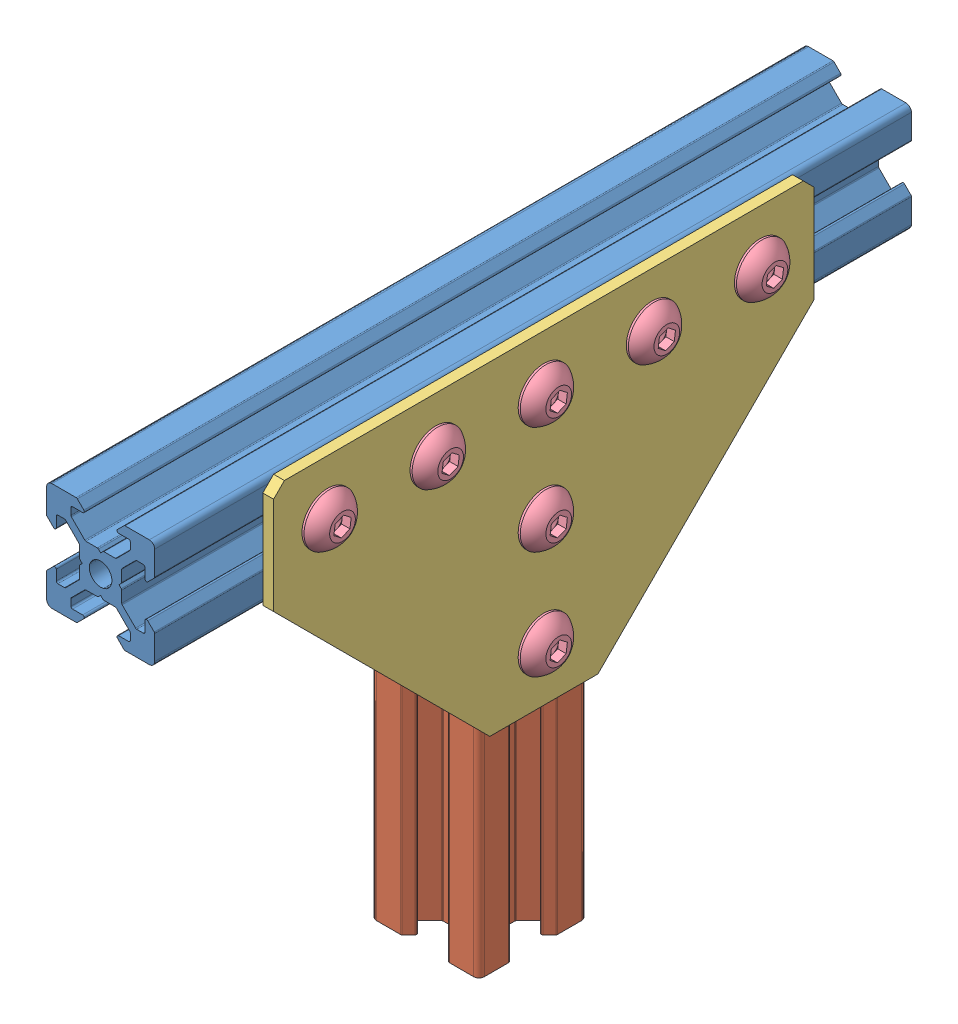
SolidWorks assembly Т-пластина 20 серия 3х5 7отв 60х100х2 усил СБ, configuration По умолчанию. Lengths in mm.
Overall size (24.75 100 140).
10 component instances, 4 part files, 19 mates.
Components (placement in the parent):
- 2020100-1: 2020100 [По умолчанию] at origin size (20 20 140)
- 202050-2: 202050 [По умолчанию] at (0 -90 70) x (1 0 0) z (0 1 0) size (20 20 80)
- Т-пластина 20 серия 3х5 7отв 60х100х2 усил.-1: Т-пластина 20 серия 3х5 7отв 60х100х2 усил. [По умолчанию] at (10 -50 70) x (0 0 -1) z (0 -1 0) size (100 2 60)
- socket button head screw_iso-5: socket button head screw_iso [ISO 7380 - M5 x 10 - 10N] at (14.75 0 90) x (-1 0 0) z (0 0.924225 0.381849) size (12.75 9.5 9.5)
- socket button head screw_iso-6: socket button head screw_iso [ISO 7380 - M5 x 10 - 10N] at (14.75 0 50) x (-1 0 0) z (0 0.924225 0.381849) size (12.75 9.5 9.5)
- socket button head screw_iso-7: socket button head screw_iso [ISO 7380 - M5 x 10 - 10N] at (14.75 -20 70) x (-1 0 0) z (0 0.924225 0.381849) size (12.75 9.5 9.5)
- socket button head screw_iso-8: socket button head screw_iso [ISO 7380 - M5 x 10 - 10N] at (14.75 -40 70) x (-1 0 0) z (0 0.924225 0.381849) size (12.75 9.5 9.5)
- socket button head screw_iso-9: socket button head screw_iso [ISO 7380 - M5 x 10 - 10N] at (14.75 0 30) x (-1 0 0) z (0 0.924225 0.381849) size (12.75 9.5 9.5)
- socket button head screw_iso-10: socket button head screw_iso [ISO 7380 - M5 x 10 - 10N] at (14.75 0 70) x (-1 0 0) z (0 0.924225 0.381849) size (12.75 9.5 9.5)
- socket button head screw_iso-11: socket button head screw_iso [ISO 7380 - M5 x 10 - 10N] at (14.75 0 110) x (-1 0 0) z (0 0.924225 0.381849) size (12.75 9.5 9.5)
Mates (geometry in assembly coordinates):
- Совпадение1: coincident aligned: plane of 2020100-1 through (10 -10 140) normal (1 0 0); plane of 202050-2 through (10 -10 60) normal (1 0 0)
- Совпадение2: coincident anti-aligned: plane of 2020100-1 through (10 -10 140) normal (0 -1 0); plane of 202050-2 through (0 -10 70) normal (0 1 0)
- Совпадение3: coincident anti-aligned: plane of 2020100-1 through (10 -10 140) normal (1 0 0); plane of Т-пластина 20 серия 3х5 7отв 60х100х2 усил.-1 through (10 -50 70) normal (-1 0 0)
- Совпадение4: coincident aligned: plane of 2020100-1 through (10 10 140) normal (0 1 0); plane of Т-пластина 20 серия 3х5 7отв 60х100х2 усил.-1 through (12 10 120) normal (0 1 0)
- Концентричный1: concentric aligned: cylinder of Т-пластина 20 серия 3х5 7отв 60х100х2 усил.-1 through (12 0 90) axis (1 0 0) radius 2.75; cylinder of socket button head screw_iso-5 through (14.75 0 90) axis (1 0 0) radius 4.75
- Совпадение6: coincident anti-aligned: plane of Т-пластина 20 серия 3х5 7отв 60х100х2 усил.-1 through (12 -50 70) normal (1 0 0); plane of socket button head screw_iso-5 through (12 -0.9546 92.3106) normal (-1 0 0)
- Концентричный2: concentric aligned: cylinder of Т-пластина 20 серия 3х5 7отв 60х100х2 усил.-1 through (12 0 50) axis (1 0 0) radius 2.75; cylinder of socket button head screw_iso-6 through (14.75 0 50) axis (1 0 0) radius 4.75
- Совпадение7: coincident anti-aligned: plane of Т-пластина 20 серия 3х5 7отв 60х100х2 усил.-1 through (12 -50 70) normal (1 0 0); plane of socket button head screw_iso-6 through (12 -0.9546 52.3106) normal (-1 0 0)
- Концентричный3: concentric aligned: cylinder of Т-пластина 20 серия 3х5 7отв 60х100х2 усил.-1 through (12 -20 70) axis (1 0 0) radius 2.75; cylinder of socket button head screw_iso-7 through (14.75 -20 70) axis (1 0 0) radius 4.75
- Совпадение8: coincident anti-aligned: plane of Т-пластина 20 серия 3х5 7отв 60х100х2 усил.-1 through (12 -50 70) normal (1 0 0); plane of socket button head screw_iso-7 through (12 -20.9546 72.3106) normal (-1 0 0)
- Концентричный4: concentric aligned: cylinder of Т-пластина 20 серия 3х5 7отв 60х100х2 усил.-1 through (12 -40 70) axis (1 0 0) radius 2.75; cylinder of socket button head screw_iso-8 through (14.75 -40 70) axis (1 0 0) radius 4.75
- Совпадение9: coincident anti-aligned: plane of Т-пластина 20 серия 3х5 7отв 60х100х2 усил.-1 through (12 -50 70) normal (1 0 0); plane of socket button head screw_iso-8 through (12 -40.9546 72.3106) normal (-1 0 0)
- Расстояние1: distance = 20 mm aligned: plane of Т-пластина 20 серия 3х5 7отв 60х100х2 усил.-1 through (12 10 120) normal (0 0 1); plane of 2020100-1 through (0 0 140) normal (0 0 1)
- Концентричный5: concentric aligned: cylinder of Т-пластина 20 серия 3х5 7отв 60х100х2 усил.-1 through (12 0 30) axis (1 0 0) radius 2.75; cylinder of socket button head screw_iso-9 through (14.75 0 30) axis (1 0 0) radius 4.75
- Совпадение13: coincident anti-aligned: plane of Т-пластина 20 серия 3х5 7отв 60х100х2 усил.-1 through (12 -50 70) normal (1 0 0); plane of socket button head screw_iso-9 through (12 -0.9546 32.3106) normal (-1 0 0)
- Концентричный6: concentric aligned: cylinder of Т-пластина 20 серия 3х5 7отв 60х100х2 усил.-1 through (12 0 70) axis (1 0 0) radius 2.75; cylinder of socket button head screw_iso-10 through (14.75 0 70) axis (1 0 0) radius 4.75
- Совпадение14: coincident anti-aligned: plane of Т-пластина 20 серия 3х5 7отв 60х100х2 усил.-1 through (12 -50 70) normal (1 0 0); plane of socket button head screw_iso-10 through (12 -0.9546 72.3106) normal (-1 0 0)
- Концентричный7: concentric aligned: cylinder of Т-пластина 20 серия 3х5 7отв 60х100х2 усил.-1 through (12 0 110) axis (1 0 0) radius 2.75; cylinder of socket button head screw_iso-11 through (14.75 0 110) axis (1 0 0) radius 4.75
- Совпадение15: coincident anti-aligned: plane of Т-пластина 20 серия 3х5 7отв 60х100х2 усил.-1 through (12 -50 70) normal (1 0 0); plane of socket button head screw_iso-11 through (12 -0.9546 112.3106) normal (-1 0 0)
